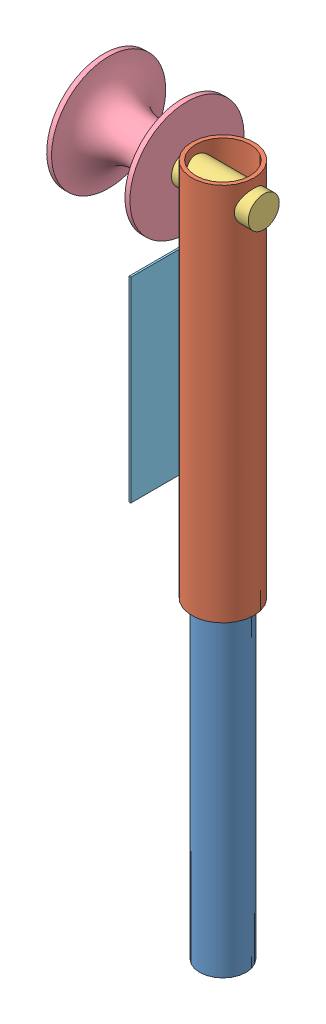
SolidWorks assembly 20 - Primary Hoist Arm, configuration Extended. Lengths in mm.
Overall size (70.01 304.97 63.96).
5 component instances, 5 part files, 10 mates.
Components (placement in the parent):
- Inner Boom-1: Inner Boom [Default] at (-6.8722 -89.581 20.3264) size (19.05 130 19.05)
- Outer Boom-1: Outer Boom [Default] at (-6.8722 38.419 20.3264) x (-0.000857 0 -1) z (1 0 -0.000857) size (25.4 155 25.4)
- Wheel Rod-1: Wheel Rod [Default] at (-60.1722 183.419 20.3721) x (0.000826 0.265442 0.964126) z (-0.000228 0.964127 -0.265442) size (12.7 70 12.7)
- Zipline Wheel 2-1: Zipline Wheel 2 [Default] at (-38.5824 203.5414 8.5084) x (-1 0 0.000857) z (-0.000435 0.861777 -0.507288) size (34 46.7 46.7)
- Alignment Plate-1: Alignment Plate [Default] at (-20.3108 78.069 45.3379) x (-0.000857 0 -1) z (1 0 -0.000857) size (50 80 0.76)
Mates (geometry in assembly coordinates):
- Concentric1: concentric aligned: cylinder of Inner Boom-1 through (-6.8722 40.419 20.3264) axis (0 -1 0) radius 9.525; cylinder of Outer Boom-1 through (-6.8722 193.419 20.3264) axis (0 -1 0) radius 11.1125
- Concentric2: concentric anti-aligned: cylinder of Outer Boom-1 through (-19.5722 183.419 20.3422) axis (0.999999 0 -0.001247) radius 6.35; cylinder of Wheel Rod-1 through (9.8278 183.419 20.3056) axis (-0.999999 0 0.001247) radius 6.35
- LimitDistance1: limit distance = 2 mm anti-aligned: plane of Outer Boom-1 through (-6.8722 38.419 20.3264) normal (0 -1 0); plane of Inner Boom-1 through (-6.8722 40.419 20.3264) normal (0 1 0)
- Distance1: distance = 4 mm aligned: plane of Wheel Rod-1; cylinder of Outer Boom-1 through (-6.8722 193.419 20.3264) axis (0 -1 0) radius 12.7
- Concentric3: concentric aligned: cylinder of Wheel Rod-1 through (9.8278 183.419 20.3056) axis (-0.999999 0 0.001247) radius 6.35; cylinder of Zipline Wheel 2-1 through (-3.6117 183.419 20.3223) axis (-0.999999 0 0.001247) radius 6.35
- Distance2: distance = 2 mm anti-aligned: plane of Zipline Wheel 2-1; cylinder of Outer Boom-1 through (-6.8722 193.419 20.3264) axis (0 -1 0) radius 12.7
- Tangent3: tangent anti-aligned: cylinder of Outer Boom-1 through (-6.8722 193.419 20.3264) axis (0 -1 0) radius 12.7; plane of Alignment Plate-1
- Parallel1: parallel anti-aligned: plane of Zipline Wheel 2-1; plane of Alignment Plate-1
- Distance4: distance = 2 mm anti-aligned: plane of Alignment Plate-1 through (-19.5411 158.069 45.3422) normal (0 1 0); cylinder of Zipline Wheel 2-1 through (-21.5722 183.419 20.3447) axis (0.999999 0 -0.001247) radius 23.35
- Coincident2: coincident: unknown of ?
